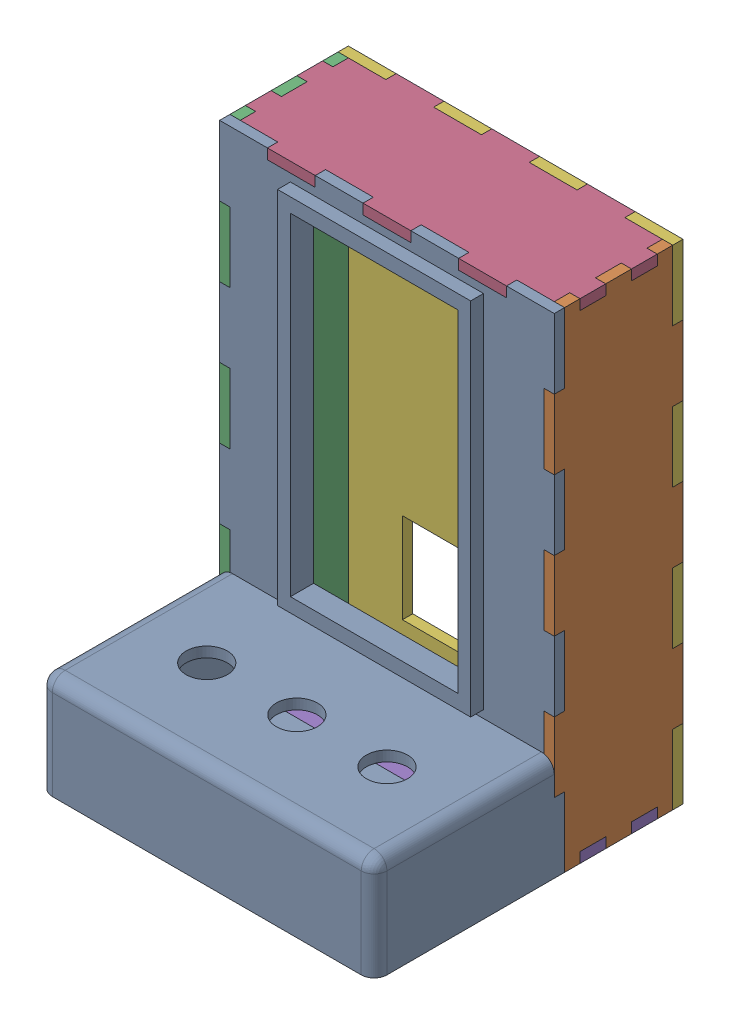
SolidWorks assembly Assem tetris 2, configuration Default. Lengths in mm.
Overall size (130 190 120).
6 component instances, 4 part files, 15 mates.
Components (placement in the parent):
- tetris voorkant2-1: tetris voorkant2 [Default] at (-172.0132 -96.04 24.176) size (130 190 74)
- tetris zijkant 2-2: tetris zijkant 2 [Default] at (-42.0132 -96.04 24.176) x (0 0 -1) z (1 0 0) size (50 190 4)
- tetris zijkant 2-3: tetris zijkant 2 [Default] at (-172.0132 -96.04 -25.824) x (0 0 1) z (-1 0 0) size (50 190 4)
- tetris bovenkant 2-1: tetris bovenkant 2 [Default] at (-172.0132 93.96 24.176) x (1 0 0) z (0 1 0) size (130 50 4)
- tetris bovenkant 2-2: tetris bovenkant 2 [Default] at (-172.0132 -92.04 24.176) x (1 0 0) z (0 1 0) size (130 50 4)
- tetris achterkant 2-1: tetris achterkant 2 [Default] at (-172.0132 -96.04 -21.824) size (130 190 4)
Mates (geometry in assembly coordinates):
- Coincident1: coincident anti-aligned: plane of tetris voorkant2-1 through (-46.0132 66.8172 20.176) normal (1 0 0); plane of tetris zijkant 2-2 through (-46.0132 -96.04 24.176) normal (-1 0 0)
- Coincident2: coincident aligned: line of tetris voorkant2-1 through (-42.0132 66.8172 20.176) axis (0 1 0); line of tetris zijkant 2-2 through (-42.0132 66.8172 20.176) axis (0 1 0)
- Coincident3: coincident: point of tetris voorkant2-1; point of tetris zijkant 2-2
- Coincident13: coincident anti-aligned: plane of tetris voorkant2-1 through (-168.0132 66.8172 20.176) normal (-1 0 0); plane of tetris zijkant 2-3 through (-168.0132 -96.04 -25.824) normal (1 0 0)
- Coincident14: coincident aligned: line of tetris voorkant2-1 through (-172.0132 -68.8971 20.176) axis (0 -1 0); line of tetris zijkant 2-3 through (-172.0132 -68.8971 20.176) axis (0 -1 0)
- Coincident15: coincident: point of tetris voorkant2-1; point of tetris zijkant 2-3
- Coincident16: coincident: plane of tetris voorkant2-1 through (-116.299 89.96 20.176) normal (0 1 0); plane of tetris bovenkant 2-1 through (-172.0132 89.96 24.176) normal (0 -1 0)
- Coincident17: coincident: line of tetris zijkant 2-2 through (-42.0132 89.96 14.176) axis (0 0 -1); line of tetris bovenkant 2-1 through (-42.0132 89.96 14.176) axis (0 0 -1)
- Coincident18: coincident: point of tetris zijkant 2-2; point of tetris bovenkant 2-1
- Coincident19: coincident: plane of tetris zijkant 2-2 through (-46.0132 -92.04 14.176) normal (0 -1 0); plane of tetris bovenkant 2-2 through (-172.0132 -92.04 24.176) normal (0 1 0)
- Coincident20: coincident: line of tetris voorkant2-1 through (-153.4418 -96.04 24.176) axis (1 0 0); line of tetris bovenkant 2-2 through (-153.4418 -96.04 24.176) axis (1 0 0)
- Coincident21: coincident: point of tetris zijkant 2-3; point of tetris bovenkant 2-2
- Coincident22: coincident: plane of tetris bovenkant 2-1 through (-97.7275 89.96 -21.824) normal (0 0 -1); plane of tetris achterkant 2-1 through (-172.0132 -96.04 -21.824) normal (0 0 1)
- Coincident23: coincident: line of tetris zijkant 2-3 through (-172.0132 66.8172 -21.824) axis (0 1 0); line of tetris achterkant 2-1 through (-172.0132 93.96 -21.824) axis (0 -1 0)
- Coincident24: coincident: point of tetris bovenkant 2-2; point of tetris achterkant 2-1
